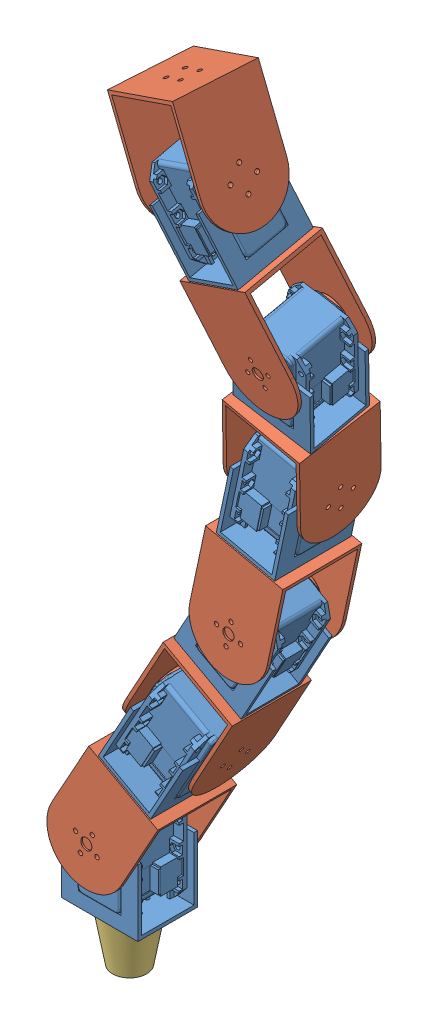
SolidWorks assembly TestModule, configuration Default. Lengths in mm.
Overall size (181.67 506.56 90.75).
13 component instances, 3 part files, 26 mates.
Components (placement in the parent):
- M+B-1: M+B [Default] at (10.1837 -8.088 4.2515) size (43.6 53.12 41.85)
- C+H-1: C+H [Default] at (-26.554 34.3068 66.0554) x (0 0 -1) z (0.874995 -0.484132 0) size (45 66 45)
- M+B-2: M+B [Default] at (20.7989 89.0767 65.6675) x (0 0 -1) z (0.874995 -0.484132 0) size (43.6 53.12 41.85)
- C+H-2: C+H [Default] at (44.492 92.1131 -8.7281) x (0.874995 -0.484132 0) z (-0.003496 -0.006319 0.999974) size (45 66 45)
- C+H-3: C+H [Default] at (111.9156 252.0627 -8.8575) x (0.976807 -0.214116 -0.001496) z (-0.046153 -0.217363 0.974999) size (45 66 45)
- M+B-3: M+B [Default] at (87.5775 230.446 68.8016) x (0.000248 0.008116 -0.999967) z (0.976807 -0.214116 -0.001496) size (43.6 53.12 41.85)
- C+H-4: C+H [Default] at (57.8355 164.434 68.6464) x (0.000248 0.008116 -0.999967) z (0.976807 -0.214116 -0.001496) size (45 66 45)
- M+B-4: M+B [Default] at (78.9372 153.8991 6.7602) x (0.875002 -0.484105 -0.003712) z (-0.000248 -0.008116 0.999967) size (43.6 53.12 41.85)
- C+H-5: C+H [Default] at (115.2123 386.88 31.2987) x (0.920184 0.379454 0.096311) z (-0.09221 -0.029013 0.995317) size (45 66 45)
- M+B-5: M+B [Default] at (98.0046 361.6059 95.2924) x (0.009049 0.225332 -0.97424) z (0.920184 0.379454 0.096311) size (43.6 53.12 41.85)
- C+H-6: C+H [Default] at (112.0028 292.2819 79.7866) x (0.009049 0.225332 -0.97424) z (0.920184 0.379454 0.096311) size (45 66 45)
- M+B-6: M+B [Default] at (124.7914 316.42 22.0502) x (0.977855 -0.205712 -0.038497) z (-0.009049 -0.225332 0.97424) size (43.6 53.12 41.85)
- head-1: head [Default] at (31.5915 -12.8397 43.1374) x (1 0 0) z (0 -1 0) size (30 30 30)
Mates (geometry in assembly coordinates):
- Concentric1: concentric anti-aligned: cylinder of M+B-1 through (31.0671 28.2503 60.4341) axis (0 0 1) radius 2.85; cylinder of C+H-1 through (31.0671 28.2503 65.2841) axis (0 0 -1) radius 1.5
- Coincident1: coincident anti-aligned: plane of M+B-1 through (28.1031 25.2801 65.2841) normal (0 0 1); plane of C+H-1 through (31.4712 75.4555 65.2841) normal (0 0 -1)
- Concentric2: concentric aligned: cylinder of C+H-1 through (47.5453 47.7045 39.7841) axis (0.484132 0.874995 0) radius 1.25; cylinder of M+B-2 through (25.13 7.1922 39.7841) axis (0.484132 0.874995 0) radius 1.25
- Concentric3: concentric aligned: cylinder of C+H-1 through (47.5453 47.7045 49.7841) axis (0.484132 0.874995 0) radius 1.25; cylinder of M+B-2 through (25.13 7.1922 49.7841) axis (0.484132 0.874995 0) radius 1.25
- Coincident2: coincident anti-aligned: plane of C+H-1 through (71.8142 55.4196 67.2841) normal (0.484132 0.874995 0); plane of M+B-2 through (52.1268 66.3126 44.7841) normal (-0.484132 -0.874995 0)
- Concentric4: concentric anti-aligned: cylinder of M+B-2 through (87.551 93.6728 44.7841) axis (0.874995 -0.484132 0) radius 2.85; cylinder of C+H-2 through (91.7947 91.3247 44.7841) axis (-0.874995 0.484132 0) radius 1.5
- Coincident3: coincident anti-aligned: plane of M+B-2 through (90.3567 88.7258 47.7481) normal (0.874995 -0.484132 0); plane of C+H-2 through (111.9643 127.7782 22.5844) normal (-0.874995 0.484132 0)
- Coincident4: coincident anti-aligned: plane of C+H-3 through (164.6961 297.4536 35.4016) normal (-0.976807 0.214116 0.001496); plane of M+B-3 through (154.3438 250.1165 51.0578) normal (0.976807 -0.214116 -0.001496)
- Coincident5: coincident anti-aligned: plane of C+H-4 through (101.695 220.4428 68.3405) normal (0.000248 0.008116 -0.999967); plane of M+B-4 through (110.7557 173.9251 67.9652) normal (-0.000248 -0.008116 0.999967)
- Coincident6: coincident anti-aligned: plane of M+B-3 through (124.1065 217.7451 47.8235) normal (-0.214121 -0.976775 -0.007981); plane of C+H-4 through (146.0791 212.7449 70.2891) normal (0.214121 0.976775 0.007981)
- Concentric5: concentric anti-aligned: cylinder of C+H-4 through (114.7872 175.089 67.9757) axis (0.000248 0.008116 -0.999967) radius 1.5; cylinder of M+B-4 through (114.7884 175.1284 63.1258) axis (-0.000248 -0.008116 0.999967) radius 2.85
- Concentric6: concentric aligned: cylinder of M+B-3 through (115.1143 153.3389 52.2987) axis (0.214121 0.976775 0.007981) radius 1.25; cylinder of C+H-4 through (125.0281 198.5636 52.6682) axis (0.214121 0.976775 0.007981) radius 1.25
- Concentric7: concentric anti-aligned: cylinder of C+H-3 through (154.9806 253.0417 48.1176) axis (-0.976807 0.214116 0.001496) radius 1.5; cylinder of M+B-3 through (150.243 254.0802 48.1249) axis (0.976807 -0.214116 -0.001496) radius 2.85
- Concentric8: concentric aligned: cylinder of M+B-3 through (115.1167 153.4201 42.299) axis (0.214121 0.976775 0.007981) radius 1.25; cylinder of C+H-4 through (125.0305 198.6448 42.6685) axis (0.214121 0.976775 0.007981) radius 1.25
- Coincident7: coincident anti-aligned: plane of C+H-2 through (75.1504 150.0615 67.5976) normal (0.484119 0.874972 0.007221); plane of M+B-4 through (94.9003 139.3198 45.0797) normal (-0.484119 -0.874972 -0.007221)
- Coincident8: coincident aligned: circle of C+H-2; cylinder of M+B-4 through (59.1531 85.0016 49.6302) axis (0.484119 0.874972 0.007221) radius 1.25
- Coincident9: coincident anti-aligned: plane of C+H-5 through (126.4179 461.1091 65.4961) normal (-0.920184 -0.379454 -0.096311); plane of M+B-5 through (141.2683 418.7457 90.5169) normal (0.920184 0.379454 0.096311)
- Coincident10: coincident anti-aligned: plane of C+H-6 through (115.3115 361.6793 95.0765) normal (0.009049 0.225332 -0.97424); plane of M+B-6 through (148.7386 330.7581 88.2352) normal (-0.009049 -0.225332 0.97424)
- Coincident11: coincident anti-aligned: plane of M+B-5 through (135.4184 376.6311 77.6794) normal (0.391381 -0.897352 -0.203914); plane of C+H-6 through (155.9189 380.0988 101.7668) normal (-0.391381 0.897352 0.203914)
- Concentric9: concentric anti-aligned: cylinder of C+H-6 through (152.258 332.977 88.7811) axis (0.009049 0.225332 -0.97424) radius 1.5; cylinder of M+B-6 through (152.3019 334.0698 84.0561) axis (-0.009049 -0.225332 0.97424) radius 2.85
- Concentric10: concentric aligned: cylinder of M+B-5 through (165.3356 319.2533 69.8186) axis (-0.391381 0.897352 0.203914) radius 1.25; cylinder of C+H-6 through (147.2146 360.8007 79.2598) axis (-0.391381 0.897352 0.203914) radius 1.25
- Concentric11: concentric anti-aligned: cylinder of C+H-5 through (140.1327 422.0789 88.2349) axis (-0.920184 -0.379454 -0.096311) radius 1.5; cylinder of M+B-5 through (135.6698 420.2386 87.7678) axis (0.920184 0.379454 0.096311) radius 2.85
- Concentric12: concentric aligned: cylinder of M+B-5 through (165.4261 321.5066 60.0762) axis (-0.391381 0.897352 0.203914) radius 1.25; cylinder of C+H-6 through (147.3051 363.054 69.5174) axis (-0.391381 0.897352 0.203914) radius 1.25
- Coincident12: coincident anti-aligned: plane of C+H-3 through (121.0347 298.7838 79.7853) normal (0.209088 0.952317 0.222204); plane of M+B-6 through (143.8711 298.9388 57.6329) normal (-0.209088 -0.952317 -0.222204)
- Concentric13: concentric aligned: cylinder of C+H-3 through (135.0684 281.2228 58.5859) axis (0.209088 0.952317 0.222204) radius 1.25; cylinder of M+B-6 through (125.3876 237.1305 48.2978) axis (0.209088 0.952317 0.222204) radius 1.25
- Coincident14: coincident anti-aligned: plane of M+B-1 through (31.0671 -12.8397 42.6841) normal (0 -1 0); plane of head-1 through (31.5915 -12.8397 43.1374) normal (0 1 0)
